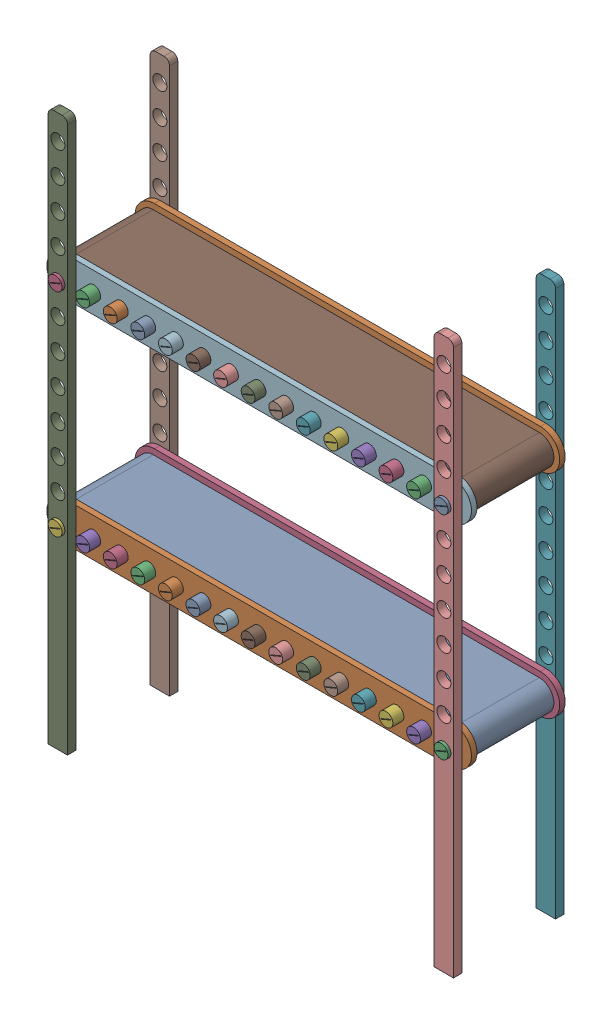
SolidWorks assembly FULL CONVEYOR, configuration Default. Lengths in mm.
Overall size (770 1000 210).
42 component instances, 4 part files, 18 mates.
Components (placement in the parent):
- FULL CONVEYOR 1-3: FULL CONVEYOR 1 [Default] at (0 124.5063 0) size (770 70 210)
  - CONVEYOR-3: CONVEYOR [Default] at (-343.7007 225.4937 -62.3126) size (753 53 146)
  - JOINT-5: JOINT [Default] at (-343.7007 225.4937 12.6874) size (770 70 10)
  - ROLLER FOR CONVEYOR-51: ROLLER FOR CONVEYOR [Default] at (356.2993 225.4937 -62.3126) x (-0.386475 0.9223 0) z (0 0 1) size (50 50 210)
  - JOINT-6: JOINT [Default] at (-343.7007 225.4937 -147.3126) size (770 70 10)
  - ROLLER FOR CONVEYOR-52: ROLLER FOR CONVEYOR [Default] at (306.2993 225.4937 -62.3126) x (-0.386475 0.9223 0) z (0 0 1) size (50 50 210)
  - ROLLER FOR CONVEYOR-53: ROLLER FOR CONVEYOR [Default] at (256.2993 225.4937 -62.3126) x (-0.386475 0.9223 0) z (0 0 1) size (50 50 210)
  - ROLLER FOR CONVEYOR-54: ROLLER FOR CONVEYOR [Default] at (206.2993 225.4937 -62.3126) x (-0.386475 0.9223 0) z (0 0 1) size (50 50 210)
  - ROLLER FOR CONVEYOR-55: ROLLER FOR CONVEYOR [Default] at (156.2993 225.4937 -62.3126) x (-0.386475 0.9223 0) z (0 0 1) size (50 50 210)
  - ROLLER FOR CONVEYOR-56: ROLLER FOR CONVEYOR [Default] at (106.2993 225.4937 -62.3126) x (-0.386475 0.9223 0) z (0 0 1) size (50 50 210)
  - ROLLER FOR CONVEYOR-57: ROLLER FOR CONVEYOR [Default] at (56.2993 225.4937 -62.3126) x (-0.386475 0.9223 0) z (0 0 1) size (50 50 210)
  - ROLLER FOR CONVEYOR-58: ROLLER FOR CONVEYOR [Default] at (6.2993 225.4937 -62.3126) x (-0.386475 0.9223 0) z (0 0 1) size (50 50 210)
  - ROLLER FOR CONVEYOR-59: ROLLER FOR CONVEYOR [Default] at (-43.7007 225.4937 -62.3126) x (-0.386475 0.9223 0) z (0 0 1) size (50 50 210)
  - ROLLER FOR CONVEYOR-60: ROLLER FOR CONVEYOR [Default] at (-93.7007 225.4937 -62.3126) x (-0.386475 0.9223 0) z (0 0 1) size (50 50 210)
  - ROLLER FOR CONVEYOR-61: ROLLER FOR CONVEYOR [Default] at (-143.7007 225.4937 -62.3126) x (-0.386475 0.9223 0) z (0 0 1) size (50 50 210)
  - ROLLER FOR CONVEYOR-62: ROLLER FOR CONVEYOR [Default] at (-193.7007 225.4937 -62.3126) x (-0.386475 0.9223 0) z (0 0 1) size (50 50 210)
  - ROLLER FOR CONVEYOR-63: ROLLER FOR CONVEYOR [Default] at (-243.7007 225.4937 -62.3126) x (-0.386475 0.9223 0) z (0 0 1) size (50 50 210)
  - ROLLER FOR CONVEYOR-64: ROLLER FOR CONVEYOR [Default] at (-293.7007 225.4937 -62.3126) x (-0.386475 0.9223 0) z (0 0 1) size (50 50 210)
  - ROLLER FOR CONVEYOR-65: ROLLER FOR CONVEYOR [Default] at (-343.7007 225.4937 -62.3126) x (-0.386475 0.9223 0) z (0 0 1) size (50 50 210)
- NEW STAND-1: NEW STAND [Default] at (356.2993 500 -154.8126) size (35 1000 15)
- NEW STAND-2: NEW STAND [Default] at (-343.7007 500 -154.8126) size (35 1000 15)
- NEW STAND-3: NEW STAND [Default] at (-343.7007 500 30.1874) size (35 1000 15)
- NEW STAND-4: NEW STAND [Default] at (356.2993 500 30.1874) size (35 1000 15)
- FULL CONVEYOR 1-6: FULL CONVEYOR 1 [Default] at (0 509.5063 0) size (770 70 210)
  - CONVEYOR-3: CONVEYOR [Default] at (-343.7007 225.4937 -62.3126) size (753 53 146)
  - JOINT-5: JOINT [Default] at (-343.7007 225.4937 12.6874) size (770 70 10)
  - ROLLER FOR CONVEYOR-51: ROLLER FOR CONVEYOR [Default] at (356.2993 225.4937 -62.3126) x (-0.386475 0.9223 0) z (0 0 1) size (50 50 210)
  - JOINT-6: JOINT [Default] at (-343.7007 225.4937 -147.3126) size (770 70 10)
  - ROLLER FOR CONVEYOR-52: ROLLER FOR CONVEYOR [Default] at (306.2993 225.4937 -62.3126) x (-0.386475 0.9223 0) z (0 0 1) size (50 50 210)
  - ROLLER FOR CONVEYOR-53: ROLLER FOR CONVEYOR [Default] at (256.2993 225.4937 -62.3126) x (-0.386475 0.9223 0) z (0 0 1) size (50 50 210)
  - ROLLER FOR CONVEYOR-54: ROLLER FOR CONVEYOR [Default] at (206.2993 225.4937 -62.3126) x (-0.386475 0.9223 0) z (0 0 1) size (50 50 210)
  - ROLLER FOR CONVEYOR-55: ROLLER FOR CONVEYOR [Default] at (156.2993 225.4937 -62.3126) x (-0.386475 0.9223 0) z (0 0 1) size (50 50 210)
  - ROLLER FOR CONVEYOR-56: ROLLER FOR CONVEYOR [Default] at (106.2993 225.4937 -62.3126) x (-0.386475 0.9223 0) z (0 0 1) size (50 50 210)
  - ROLLER FOR CONVEYOR-57: ROLLER FOR CONVEYOR [Default] at (56.2993 225.4937 -62.3126) x (-0.386475 0.9223 0) z (0 0 1) size (50 50 210)
  - ROLLER FOR CONVEYOR-58: ROLLER FOR CONVEYOR [Default] at (6.2993 225.4937 -62.3126) x (-0.386475 0.9223 0) z (0 0 1) size (50 50 210)
  - ROLLER FOR CONVEYOR-59: ROLLER FOR CONVEYOR [Default] at (-43.7007 225.4937 -62.3126) x (-0.386475 0.9223 0) z (0 0 1) size (50 50 210)
  - ROLLER FOR CONVEYOR-60: ROLLER FOR CONVEYOR [Default] at (-93.7007 225.4937 -62.3126) x (-0.386475 0.9223 0) z (0 0 1) size (50 50 210)
  - ROLLER FOR CONVEYOR-61: ROLLER FOR CONVEYOR [Default] at (-143.7007 225.4937 -62.3126) x (-0.386475 0.9223 0) z (0 0 1) size (50 50 210)
  - ROLLER FOR CONVEYOR-62: ROLLER FOR CONVEYOR [Default] at (-193.7007 225.4937 -62.3126) x (-0.386475 0.9223 0) z (0 0 1) size (50 50 210)
  - ROLLER FOR CONVEYOR-63: ROLLER FOR CONVEYOR [Default] at (-243.7007 225.4937 -62.3126) x (-0.386475 0.9223 0) z (0 0 1) size (50 50 210)
  - ROLLER FOR CONVEYOR-64: ROLLER FOR CONVEYOR [Default] at (-293.7007 225.4937 -62.3126) x (-0.386475 0.9223 0) z (0 0 1) size (50 50 210)
  - ROLLER FOR CONVEYOR-65: ROLLER FOR CONVEYOR [Default] at (-343.7007 225.4937 -62.3126) x (-0.386475 0.9223 0) z (0 0 1) size (50 50 210)
Mates (geometry in assembly coordinates):
- Coincident23: coincident anti-aligned: plane of NEW STAND-2 through (-361.2007 0 -147.3126) normal (0 -1 0)
- Coincident25: coincident anti-aligned: plane of NEW STAND-3 through (-361.2007 0 37.6874) normal (0 -1 0)
- Coincident26: coincident anti-aligned: plane of NEW STAND-4 through (338.7993 0 37.6874) normal (0 -1 0)
- Coincident27: coincident anti-aligned: plane of NEW STAND-1 through (338.7993 0 -147.3126) normal (0 -1 0)
- Concentric18: concentric aligned: cylinder of FULL CONVEYOR 1-3/ROLLER FOR CONVEYOR-65 through (-343.7007 350 -167.3126) axis (0 0 1) radius 12.5; cylinder of NEW STAND-2 through (-343.7007 350 -162.3126) axis (0 0 1) radius 12.7
- Concentric19: concentric aligned: cylinder of FULL CONVEYOR 1-3/ROLLER FOR CONVEYOR-51 through (356.2993 350 -167.3126) axis (0 0 1) radius 12.5; cylinder of NEW STAND-1 through (356.2993 350 -162.3126) axis (0 0 1) radius 12.7
- Concentric20: concentric anti-aligned: cylinder of FULL CONVEYOR 1-3/ROLLER FOR CONVEYOR-51 through (356.2993 350 42.6874) axis (0 0 -1) radius 12.5; cylinder of NEW STAND-4 through (356.2993 350 22.6874) axis (0 0 1) radius 12.7
- Concentric21: concentric anti-aligned: cylinder of FULL CONVEYOR 1-3/ROLLER FOR CONVEYOR-65 through (-343.7007 350 42.6874) axis (0 0 -1) radius 12.5; cylinder of NEW STAND-3 through (-343.7007 350 22.6874) axis (0 0 1) radius 12.7
- Coincident28: coincident anti-aligned: plane of FULL CONVEYOR 1-3/JOINT-6 through (-343.7007 350 -147.3126) normal (0 0 -1); plane of NEW STAND-1 through (356.2993 500 -147.3126) normal (0 0 1)
- Coincident29: coincident anti-aligned: plane of FULL CONVEYOR 1-3/JOINT-5 through (-343.7007 350 22.6874) normal (0 0 1); plane of NEW STAND-3 through (-343.7007 500 22.6874) normal (0 0 -1)
- Coincident30: coincident anti-aligned: plane of FULL CONVEYOR 1-3/JOINT-5 through (-343.7007 350 22.6874) normal (0 0 1); plane of NEW STAND-4 through (356.2993 500 22.6874) normal (0 0 -1)
- Coincident31: coincident anti-aligned: plane of FULL CONVEYOR 1-3/JOINT-6 through (-343.7007 350 -147.3126) normal (0 0 -1); plane of NEW STAND-2 through (-343.7007 500 -147.3126) normal (0 0 1)
- Coincident36: coincident aligned: plane of FULL CONVEYOR 1-3 through (0 124.5063 0) normal (0 0 1)
- Parallel9: parallel aligned: plane of FULL CONVEYOR 1-3 through (0 124.5063 0) normal (0 1 0)
- Coincident38: coincident aligned: plane of FULL CONVEYOR 1-3 through (0 124.5063 0) normal (1 0 0)
- Concentric33: concentric aligned: cylinder of NEW STAND-2 through (-343.7007 735 -162.3126) axis (0 0 1) radius 12.7; cylinder of FULL CONVEYOR 1-6/ROLLER FOR CONVEYOR-65 through (-343.7007 735 -167.3126) axis (0 0 1) radius 12.5
- Concentric34: concentric anti-aligned: cylinder of NEW STAND-4 through (356.2993 735 22.6874) axis (0 0 1) radius 12.7; cylinder of FULL CONVEYOR 1-6/ROLLER FOR CONVEYOR-51 through (356.2993 735 42.6874) axis (0 0 -1) radius 12.5
- Coincident41: coincident anti-aligned: plane of NEW STAND-1 through (356.2993 500 -147.3126) normal (0 0 1); plane of FULL CONVEYOR 1-6/JOINT-6 through (-343.7007 735 -147.3126) normal (0 0 -1)
